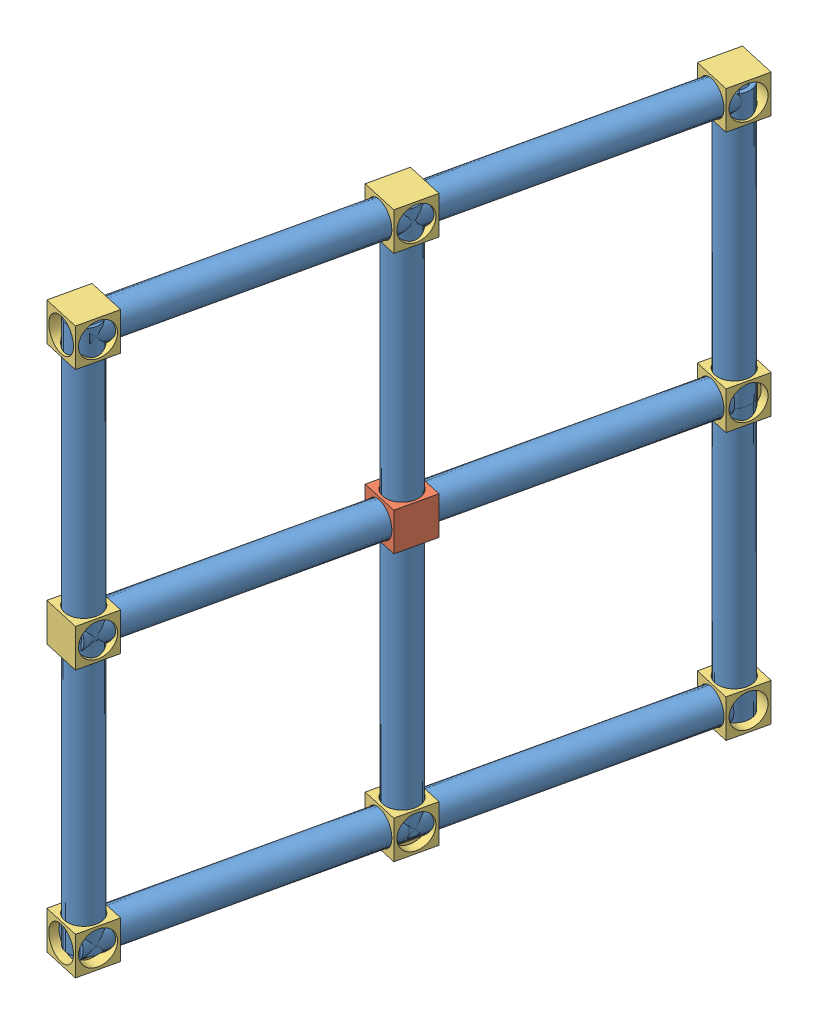
SolidWorks assembly base, configuration Default. Lengths in mm.
Overall size (139.74 479.99 483.73).
21 component instances, 3 part files, 37 mates.
Components (placement in the parent):
- 9inPVC-1: 9inPVC [Default] at (68.2891 -2.5751 -3.3804) x (0.973326 -0.067249 0.219348) z (-0.219845 0 0.975535) size (26.67 26.67 228.6)
- middleConnectorPieceNew-1: middleConnectorPieceNew [Default] at (18.7665 -18.4501 216.3694) x (-0.219845 0 0.975535) z (-0.975535 0 -0.219845) size (31.75 31.75 31.75)
- 9inPVC-2: 9inPVC [Default] at (-32.2242 -2.5751 442.6341) x (-0.641309 0.753548 -0.144525) z (0.219845 0 -0.975535) size (26.67 26.67 228.6)
- 9inPVC-3: 9inPVC [Default] at (18.7665 225.6879 216.3694) x (-0.596193 0 0.802841) z (0 -1 0) size (26.67 26.67 228.6)
- 9inPVC-4: 9inPVC [Default] at (18.7665 -231.5121 216.3694) x (-0.368817 0 -0.929502) z (0 1 0) size (26.67 26.67 228.6)
- rightAngle-3: rightAngle [Default] at (54.5744 -2.5751 -14.7331) x (0.219845 0 -0.975535) z (0 -1 0) size (31.75 31.75 31.75)
- rightAngle-4: rightAngle [Default] at (3.2799 215.874 212.8793) x (0 1 0) z (0.219845 0 -0.975535) size (31.75 31.75 31.75)
- 9inPVC-5: 9inPVC [Default] at (69.2382 215.874 -7.5918) x (0.475995 0.872882 0.10727) z (-0.219845 0 0.975535) size (26.67 26.67 228.6)
- 9inPVC-6: 9inPVC [Default] at (18.9815 215.874 215.4154) x (0.73224 -0.660753 0.165017) z (-0.219845 0 0.975535) size (26.67 26.67 228.6)
- rightAngle-5: rightAngle [Default] at (70.061 231.749 -11.2431) x (0.219845 0 -0.975535) z (-0.975535 0 -0.219845) size (31.75 31.75 31.75)
- rightAngle-6: rightAngle [Default] at (3.2799 -226.488 212.8793) x (0 -1 0) z (-0.219845 0 0.975535) size (31.75 31.75 31.75)
- 9inPVC-7: 9inPVC [Default] at (68.1507 -226.488 -2.7663) x (0.945181 0.247512 0.213005) z (-0.219845 0 0.975535) size (26.67 26.67 228.6)
- 9inPVC-8: 9inPVC [Default] at (17.894 -226.488 220.2409) x (0.635482 -0.758718 0.143211) z (-0.219845 0 0.975535) size (26.67 26.67 228.6)
- 9inPVC-9: 9inPVC [Default] at (70.061 -235.6043 -11.2431) x (0.282586 0 -0.959242) z (0 1 0) size (26.67 26.67 228.6)
- 9inPVC-10: 9inPVC [Default] at (70.061 221.5957 -11.2431) x (0.490055 0 -0.871691) z (0 -1 0) size (26.67 26.67 228.6)
- rightAngle-7: rightAngle [Default] at (73.551 -226.488 -26.7297) x (0 -1 0) z (-0.975535 0 -0.219845) size (31.75 31.75 31.75)
- rightAngle-8: rightAngle [Default] at (-30.3986 -242.363 434.533) x (-0.975535 0 -0.219845) z (0.219845 0 -0.975535) size (31.75 31.75 31.75)
- rightAngle-9: rightAngle [Default] at (-33.8886 -2.5751 450.0196) x (-0.975535 0 -0.219845) z (0 -1 0) size (31.75 31.75 31.75)
- rightAngle-10: rightAngle [Default] at (-30.3986 231.749 434.533) x (-0.975535 0 -0.219845) z (-0.219845 0 0.975535) size (31.75 31.75 31.75)
- 9inPVC-11: 9inPVC [Default] at (-30.3986 -4.8289 434.533) x (0.91731 0 0.398174) z (0 -1 0) size (26.67 26.67 228.6)
- 9inPVC-12: 9inPVC [Default] at (-30.3986 223.7711 434.533) x (0.985071 0 -0.172149) z (0 -1 0) size (26.67 26.67 228.6)
Mates (geometry in assembly coordinates):
- Concentric1: concentric anti-aligned: circle of middleConnectorPiece-1; cylinder of 9inPVC-2 through (18.0324 -2.5751 219.6268) axis (-0.219845 0 0.975535) radius 13.335
- Concentric2: concentric anti-aligned: cylinder of 9inPVC-1 through (18.0324 -2.5751 219.6268) axis (0.219845 0 -0.975535) radius 13.335; circle of middleConnectorPiece-1
- Coincident1: coincident anti-aligned: plane of 9inPVC-1 through (18.0324 -2.5751 219.6268) normal (-0.219845 0 0.975535); plane of 9inPVC-2 through (18.0324 -2.5751 219.6268) normal (0.219845 0 -0.975535)
- Concentric5: concentric anti-aligned: circle of middleConnectorPieceNew-1; cylinder of 9inPVC-3 through (18.7665 -2.9121 216.3694) axis (0 1 0) radius 13.335
- Concentric6: concentric anti-aligned: circle of middleConnectorPieceNew-1; cylinder of 9inPVC-4 through (18.7665 -2.9121 216.3694) axis (0 -1 0) radius 13.335
- Coincident2: coincident anti-aligned: plane of 9inPVC-3 through (18.7665 -2.9121 216.3694) normal (0 -1 0); plane of 9inPVC-4 through (18.7665 -2.9121 216.3694) normal (0 1 0)
- Concentric7: concentric anti-aligned: cylinder of 9inPVC-1 through (18.0324 -2.5751 219.6268) axis (0.219845 0 -0.975535) radius 13.335; circle of rightAngle-3
- Concentric8: concentric anti-aligned: cylinder of 9inPVC-3 through (18.7665 -2.9121 216.3694) axis (0 1 0) radius 13.335; circle of rightAngle-4
- Parallel3: parallel aligned: plane of middleConnectorPieceNew-1 through (37.7432 13.2999 204.3728) normal (0.975535 0 0.219845); plane of rightAngle-4 through (34.2531 215.874 219.8594) normal (0.975535 0 0.219845)
- Concentric11: concentric aligned: cylinder of rightAngle-4 through (15.2765 215.874 231.856) axis (0.219845 0 -0.975535) radius 13.716; cylinder of 9inPVC-5 through (18.9815 215.874 215.4154) axis (0.219845 0 -0.975535) radius 13.335
- Concentric12: concentric aligned: cylinder of 9inPVC-5 through (18.9815 215.874 215.4154) axis (0.219845 0 -0.975535) radius 13.335; cylinder of 9inPVC-6 through (-31.2752 215.874 438.4226) axis (0.219845 0 -0.975535) radius 13.335
- Coincident5: coincident anti-aligned: plane of 9inPVC-5 through (18.9815 215.874 215.4154) normal (-0.219845 0 0.975535); plane of 9inPVC-6 through (18.9815 215.874 215.4154) normal (0.219845 0 -0.975535)
- Concentric14: concentric anti-aligned: cylinder of 9inPVC-5 through (18.9815 215.874 215.4154) axis (0.219845 0 -0.975535) radius 13.335; cylinder of rightAngle-5 through (68.665 215.874 -5.0484) axis (-0.219845 0 0.975535) radius 13.716
- Concentric16: concentric: cylinder of 9inPVC-4 through (18.7665 -2.9121 216.3694) axis (0 -1 0) radius 13.335; circle of rightAngle-6
- Parallel5: parallel aligned: plane of middleConnectorPieceNew-1 through (37.7432 13.2999 204.3728) normal (0.975535 0 0.219845); plane of rightAngle-6 through (34.2531 -226.488 219.8594) normal (0.975535 0 0.219845)
- Concentric17: concentric anti-aligned: circle of rightAngle-6; cylinder of 9inPVC-7 through (17.894 -226.488 220.2409) axis (0.219845 0 -0.975535) radius 13.335
- Concentric18: concentric aligned: circle of rightAngle-6; cylinder of 9inPVC-8 through (-32.3626 -226.488 443.2481) axis (0.219845 0 -0.975535) radius 13.335
- Coincident9: coincident anti-aligned: plane of 9inPVC-7 through (17.894 -226.488 220.2409) normal (-0.219845 0 0.975535); plane of 9inPVC-8 through (17.894 -226.488 220.2409) normal (0.219845 0 -0.975535)
- Concentric19: concentric aligned: circle of rightAngle-3; circle of rightAngle-5
- Parallel6: parallel aligned: plane of middleConnectorPieceNew-1 through (37.7432 13.2999 204.3728) normal (0.975535 0 0.219845); plane of rightAngle-3 through (85.5476 -2.5751 -7.753) normal (0.975535 0 0.219845)
- Concentric20: concentric anti-aligned: cylinder of 9inPVC-9 through (70.061 -7.0043 -11.2431) axis (0 -1 0) radius 13.335; cylinder of 9inPVC-10 through (70.061 -7.0043 -11.2431) axis (0 1 0) radius 13.335
- Coincident13: coincident anti-aligned: plane of 9inPVC-9 through (70.061 -7.0043 -11.2431) normal (0 1 0); plane of 9inPVC-10 through (70.061 -7.0043 -11.2431) normal (0 -1 0)
- Concentric21: concentric aligned: circle of rightAngle-3; cylinder of 9inPVC-9 through (70.061 -7.0043 -11.2431) axis (0 -1 0) radius 13.335
- Parallel7: parallel aligned: plane of rightAngle-3 through (85.5476 -2.5751 -7.753) normal (0.975535 0 0.219845); plane of rightAngle-7 through (82.0576 -210.613 7.7336) normal (0.975535 0 0.219845)
- Concentric22: concentric anti-aligned: cylinder of 9inPVC-7 through (17.894 -226.488 220.2409) axis (0.219845 0 -0.975535) radius 9.525; cylinder of rightAngle-7 through (68.2462 -226.488 -3.19) axis (-0.219845 0 0.975535) radius 13.716
- Concentric23: concentric anti-aligned: cylinder of 9inPVC-9 through (70.061 -7.0043 -11.2431) axis (0 -1 0) radius 13.335; circle of rightAngle-7
- Concentric24: concentric anti-aligned: cylinder of 9inPVC-6 through (-31.2752 215.874 438.4226) axis (0.219845 0 -0.975535) radius 13.335; circle of rightAngle-10
- Parallel8: parallel aligned: plane of middleConnectorPieceNew-1 through (37.7432 13.2999 204.3728) normal (0.975535 0 0.219845); plane of rightAngle-10 through (-18.402 199.999 453.5097) normal (0.975535 0 0.219845)
- Concentric25: concentric anti-aligned: cylinder of 9inPVC-2 through (18.0324 -2.5751 219.6268) axis (-0.219845 0 0.975535) radius 13.335; circle of rightAngle-9
- Parallel9: parallel aligned: plane of middleConnectorPieceNew-1 through (37.7432 13.2999 204.3728) normal (0.975535 0 0.219845); plane of rightAngle-9 through (-11.4219 -18.4501 422.5364) normal (0.975535 0 0.219845)
- Concentric26: concentric anti-aligned: cylinder of 9inPVC-8 through (-32.3626 -226.488 443.2481) axis (0.219845 0 -0.975535) radius 13.335; circle of rightAngle-8
- Parallel11: parallel aligned: plane of middleConnectorPieceNew-1 through (37.7432 13.2999 204.3728) normal (0.975535 0 0.219845); plane of rightAngle-8 through (-11.4219 -210.613 422.5364) normal (0.975535 0 0.219845)
- Concentric27: concentric anti-aligned: circle of rightAngle-8; circle of rightAngle-9
- Concentric28: concentric anti-aligned: circle of rightAngle-9; circle of rightAngle-10
- Concentric29: concentric aligned: cylinder of 9inPVC-11 through (-30.3986 -233.4289 434.533) axis (0 1 0) radius 13.335; cylinder of 9inPVC-12 through (-30.3986 -4.8289 434.533) axis (0 1 0) radius 13.335
- Coincident20: coincident anti-aligned: plane of 9inPVC-11 through (-30.3986 -4.8289 434.533) normal (0 1 0); plane of 9inPVC-12 through (-30.3986 -4.8289 434.533) normal (0 -1 0)
- Concentric30: concentric anti-aligned: circle of rightAngle-9; cylinder of 9inPVC-11 through (-30.3986 -233.4289 434.533) axis (0 1 0) radius 13.335
